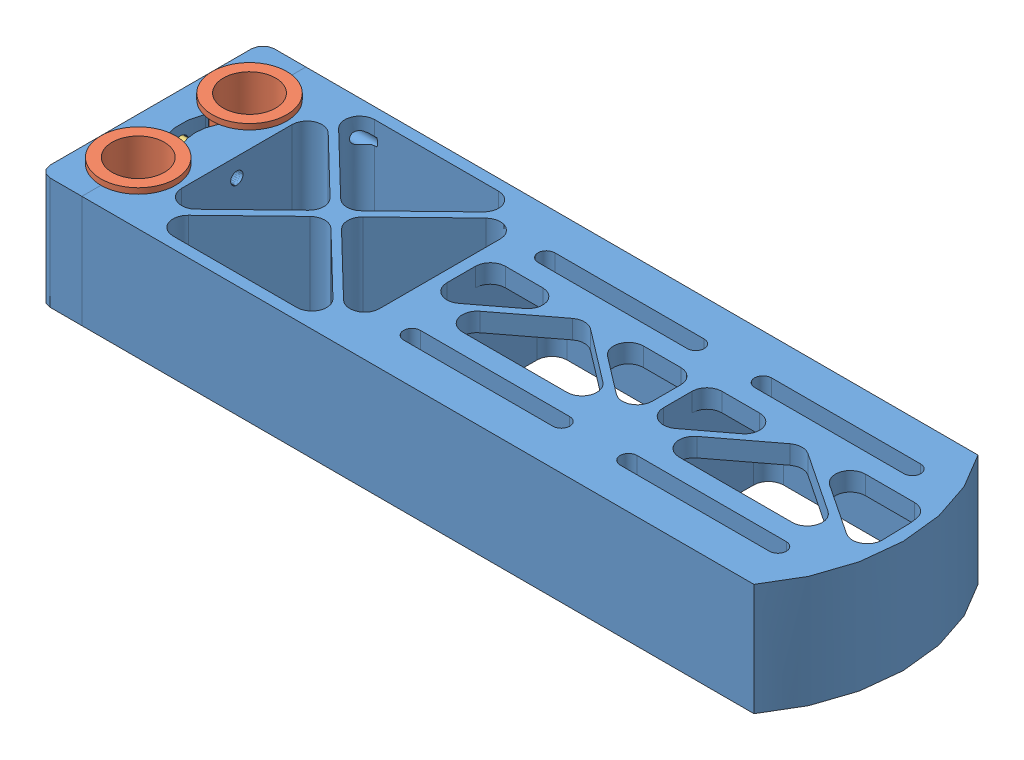
SolidWorks assembly Roll, configuration По умолчанию. Lengths in mm.
Overall size (201.5 33 60).
5 component instances, 3 part files, 8 mates.
Components (placement in the parent):
- Axis_roll_w_vtulka_v.1.0-1: Axis_roll_w_vtulka_v.1.0 [wo_double_scoba] at (-92.1851 -13.4281 31.3635) size (201.5 30 60)
- Vtulka-1: Vtulka [По умолчанию] at (-92.1851 18.0719 16.2635) x (0 -1 0) z (0 0 1) size (33 20 20)
- Vtulka-2: Vtulka [По умолчанию] at (-92.1851 18.0719 -13.5365) x (0 -1 0) z (0 0 1) size (33 20 20)
- socket head cap screw_din_1-2: socket head cap screw_din_1 [DIN 912 M4 x 16 --- 16N] at (-103.6851 11.5719 1.3635) size (20 7 7)
- socket head cap screw_din_1-3: socket head cap screw_din_1 [DIN 912 M4 x 16 --- 16N] at (-103.6851 -8.4281 1.3635) size (20 7 7)
Mates (geometry in assembly coordinates):
- Концентричный1: concentric anti-aligned: cylinder of Axis_roll_w_vtulka_v.1.0-1 through (-92.1851 -13.4281 16.2635) axis (0 1 0) radius 8.5; cylinder of Vtulka-1 through (-92.1851 -14.9281 16.2635) axis (0 -1 0) radius 8.5
- Совпадение1: coincident anti-aligned: plane of Axis_roll_w_vtulka_v.1.0-1 through (-92.1851 16.5719 16.2635) normal (0 1 0); plane of Vtulka-1 through (-92.1851 16.5719 6.2635) normal (0 -1 0)
- Концентричный2: concentric anti-aligned: cylinder of Axis_roll_w_vtulka_v.1.0-1 through (-92.1851 -13.4281 -13.5365) axis (0 1 0) radius 8.5; cylinder of Vtulka-2 through (-92.1851 -14.9281 -13.5365) axis (0 -1 0) radius 8.5
- Совпадение2: coincident anti-aligned: plane of Axis_roll_w_vtulka_v.1.0-1 through (-92.1851 16.5719 16.2635) normal (0 1 0); plane of Vtulka-2 through (-92.1851 16.5719 -23.5365) normal (0 -1 0)
- Концентричный3: concentric aligned: cylinder of Axis_roll_w_vtulka_v.1.0-1 through (-103.6851 11.5719 1.3635) axis (-1 0 0) radius 2.25; cylinder of socket head cap screw_din_1-2 through (-135.4351 11.5719 1.3635) axis (-1 0 0) radius 3.5
- Совпадение3: coincident anti-aligned: plane of Axis_roll_w_vtulka_v.1.0-1 through (-99.6851 13.8219 1.3635) normal (-1 0 0); plane of socket head cap screw_din_1-2 through (-99.6851 15.0719 1.3635) normal (1 0 0)
- Концентричный4: concentric aligned: cylinder of Axis_roll_w_vtulka_v.1.0-1 through (-103.6851 -8.4281 1.3635) axis (-1 0 0) radius 2.25; cylinder of socket head cap screw_din_1-3 through (-135.4351 -8.4281 1.3635) axis (-1 0 0) radius 3.5
- Совпадение4: coincident anti-aligned: plane of Axis_roll_w_vtulka_v.1.0-1 through (-99.6851 -6.1781 1.3635) normal (-1 0 0); plane of socket head cap screw_din_1-3 through (-99.6851 -4.9281 1.3635) normal (1 0 0)
